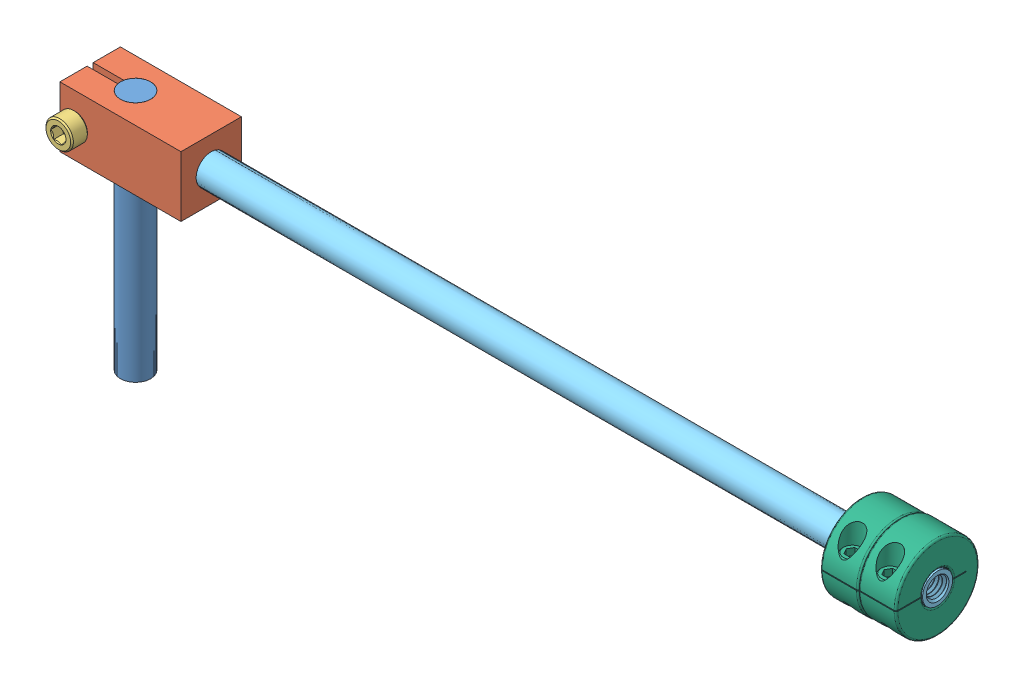
SolidWorks assembly PendulumArm, configuration Default. Lengths in mm.
Overall size (178.79 55.9 18.78).
7 component instances, 6 part files, 12 mates.
Components (placement in the parent):
- EncoderShaft-1: EncoderShaft [Default] at (-3.379 -24.9057 1.4472) size (6.35 50.8 6.35)
- Clamp-1: Clamp [Default] at (12.4973 13.1943 7.7941) x (0 1 0) z (0.000196 0 1) size (12.7 25.4 12.7)
- 6_32CapScrew-1: 6_32CapScrew [90128A148] at (-9.7302 19.5443 -4.9016) x (-0.923728 -0.383049 0.000181) z (-0.000196 0 -1) size (5.74 5.74 17.06)
- 10_32SetScrew-1: 10_32SetScrew [90289A344] at (12.5677 19.5443 1.4441) x (-0.000016 0.996648 -0.081814) z (1 0 -0.000196) size (4.88 4.93 16.29)
- QuarterInchThreadedRod-1: QuarterInchThreadedRod [6516K51] at (88.696 19.5443 1.4291) x (1 0 -0.000196) z (0 1 0) size (153.23 6.35 6.35)
- ShaftCollar-1: ShaftCollar [6435K12] at (160.9273 19.6316 1.415) x (-0.000196 0 -1) z (1 0 -0.000196) size (17.46 20.18 7.94)
- ShaftCollar-2: ShaftCollar [6435K12] at (152.9898 19.457 1.4165) x (-0.000196 0 -1) z (1 0 -0.000196) size (17.46 20.18 7.94)
Mates (geometry in assembly coordinates):
- Coincident1: coincident aligned: plane of EncoderShaft-1 through (-3.379 25.8943 1.4472) normal (0 1 0); plane of Clamp-1 through (-12.9027 25.8943 7.7991) normal (0 1 0)
- Coincident2: coincident aligned: circle of EncoderShaft-1; circle of Clamp-1
- Coincident3: coincident anti-aligned: plane of Clamp-1; plane of 6_32CapScrew-1
- Concentric1: concentric anti-aligned: circle of Clamp-1; circle of 6_32CapScrew-1
- Concentric2: concentric aligned: circle of Clamp-1; circle of 10_32SetScrew-1
- Distance1: distance = 7.62 mm aligned: plane of 10_32SetScrew-1; plane of Clamp-1
- Concentric3: concentric aligned: circle of 10_32SetScrew-1; circle of QuarterInchThreadedRod-1
- Coincident5: coincident anti-aligned: plane of Clamp-1; plane of QuarterInchThreadedRod-1
- Concentric4: concentric anti-aligned: circle of QuarterInchThreadedRod-1; circle of ShaftCollar-1
- Concentric5: concentric aligned: circle of QuarterInchThreadedRod-1; circle of ShaftCollar-2
- Coincident7: coincident aligned: plane of QuarterInchThreadedRod-1 through (164.896 19.5443 1.4142) normal (1 0 -0.000196); plane of ShaftCollar-1 through (164.896 19.719 1.4142) normal (1 0 -0.000196)
- Coincident8: coincident anti-aligned: plane of ShaftCollar-1 through (156.9585 19.719 1.4158) normal (-1 0 0.000196); plane of ShaftCollar-2 through (156.9585 19.5443 1.4158) normal (1 0 -0.000196)
